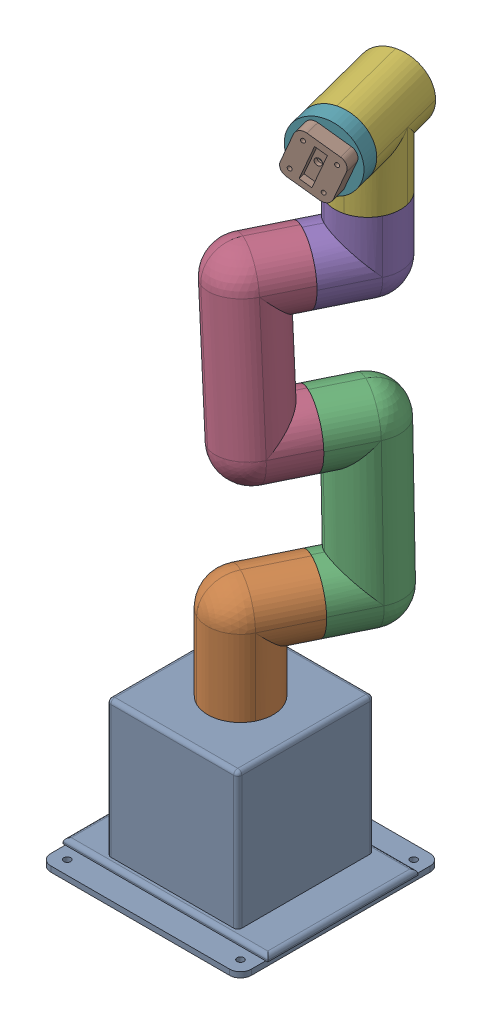
SolidWorks assembly Assembly, configuration Default. Lengths in mm.
Overall size (150 481.39 181.21).
8 component instances, 8 part files, 16 mates.
Components (placement in the parent):
- Base-1: Base [Default] at (-156.52 -42.235 111.2873) size (150 108 147)
- link1-1: link1 [Default] at (-70.5595 61.765 88.41) x (0.44088 0 -0.897566) z (0.897566 0 0.44088) size (70.5 87.5 48)
- Link2-1: Link2 [Default] at (-41.5362 169.7826 24.1204) x (0.44088 0 -0.897566) z (0.896677 0.044507 0.440443) size (63 150 48)
- Link3-1: Link3 [Default] at (-98.0076 265.1571 13.0938) x (-0.44088 0 0.897566) z (-0.891872 -0.112462 -0.438083) size (63 145 48)
- Link4-1: Link4 [Default] at (-43.4238 340.0485 -1.8746) x (0 -1 0) z (0.897566 0 0.44088) size (78 60 48)
- Link5-1: Link5 [Default] at (-31.2213 428.0485 6.6766) x (0 -1 0) z (0.96839 0 -0.249442) size (73 70 48)
- Link6-1: Link6 [Default] at (-51.2199 404.0485 25.2522) x (0.901393 -0.365487 -0.232184) z (0.353934 0.930816 -0.091168) size (48 13 48)
- Robot Gripper Holder-1: Robot Gripper Holder [Default] at (-51.2199 404.0485 25.2522) x (0.901393 -0.365487 -0.232184) z (0.249442 0 0.96839) size (34.29 34.29 11)
Mates (geometry in assembly coordinates):
- Concentric1: concentric aligned: cylinder of Base-1 through (-81.52 46.765 56.2873) axis (0 1 0) radius 5; cylinder of link1-1 through (-81.52 54.265 56.2873) axis (0 1 0) radius 5
- Coincident1: coincident anti-aligned: plane of Base-1 through (-156.52 61.765 111.2873) normal (0 1 0); plane of link1-1 through (-70.5595 61.765 88.41) normal (0 -1 0)
- Coincident2: coincident anti-aligned: plane of link1-1 through (-42.7841 61.765 31.8633) normal (0.44088 0 -0.897566); plane of Link2-1 through (-44.8428 169.7826 30.8521) normal (-0.44088 0 0.897566)
- Concentric2: concentric aligned: cylinder of link1-1 through (-61.0191 117.765 14.5505) axis (-0.44088 0 0.897566) radius 5; cylinder of Link2-1 through (-57.7125 117.765 7.8187) axis (-0.44088 0 0.897566) radius 5
- Coincident4: coincident anti-aligned: plane of Link2-1 through (-44.8428 169.7826 30.8521) normal (-0.44088 0 0.897566); plane of Link3-1 through (-94.701 265.1571 6.362) normal (0.44088 0 -0.897566)
- Concentric3: concentric aligned: cylinder of Link2-1 through (-71.707 219.6639 26.0125) axis (0.44088 0 -0.897566) radius 5; cylinder of Link3-1 through (-75.0136 219.6639 32.7442) axis (0.44088 0 -0.897566) radius 5
- Coincident5: coincident anti-aligned: plane of Link3-1 through (-94.701 265.1571 6.362) normal (0.44088 0 -0.897566); plane of Link4-1 through (-56.6502 340.0485 25.0524) normal (-0.44088 0 0.897566)
- Concentric4: concentric aligned: cylinder of Link3-1 through (-74.8852 316.0485 7.7395) axis (-0.44088 0 0.897566) radius 5; cylinder of Link4-1 through (-71.5786 316.0485 1.0078) axis (-0.44088 0 0.897566) radius 5
- Coincident7: coincident anti-aligned: plane of Link4-1 through (-43.4238 355.0485 -1.8746) normal (0 1 0); plane of Link5-1 through (-31.2213 355.0485 6.6766) normal (0 -1 0)
- Concentric5: concentric aligned: cylinder of Link4-1 through (-62.3201 370.0485 -17.8411) axis (0 -1 0) radius 5; cylinder of Link5-1 through (-62.3201 370.0485 -17.8411) axis (0 -1 0) radius 5
- Coincident8: coincident anti-aligned: plane of Link5-1 through (-31.2213 428.0485 6.6766) normal (0.249442 0 0.96839); plane of Link6-1 through (-54.4627 404.0485 12.6632) normal (-0.249442 0 -0.96839)
- Concentric6: concentric aligned: cylinder of Link5-1 through (-51.9683 404.0485 22.3471) axis (-0.249442 0 -0.96839) radius 5; cylinder of Link6-1 through (-51.9683 404.0485 22.3471) axis (-0.249442 0 -0.96839) radius 5
- Concentric7: concentric anti-aligned: cylinder of Link6-1 through (-59.2375 418.3079 19.0563) axis (0.249442 0 0.96839) radius 1.5; cylinder of Robot Gripper Holder-1 through (-50.9868 418.3079 51.0876) axis (-0.249442 0 -0.96839) radius 1.5
- Concentric10: concentric anti-aligned: cylinder of Link6-1 through (-67.0241 397.8299 21.062) axis (0.249442 0 0.96839) radius 1.5; cylinder of Robot Gripper Holder-1 through (-62.2847 397.8299 39.4614) axis (-0.249442 0 -0.96839) radius 1.5
- Concentric11: concentric anti-aligned: cylinder of Link6-1 through (-47.1934 389.7892 15.9539) axis (0.249442 0 0.96839) radius 1.5; cylinder of Robot Gripper Holder-1 through (-42.454 389.7892 34.3533) axis (-0.249442 0 -0.96839) radius 1.5
- Coincident9: coincident anti-aligned: plane of Link6-1 through (-51.2199 404.0485 25.2522) normal (0.249442 0 0.96839); plane of Robot Gripper Holder-1 through (-51.2199 404.0485 25.2522) normal (-0.249442 0 -0.96839)
